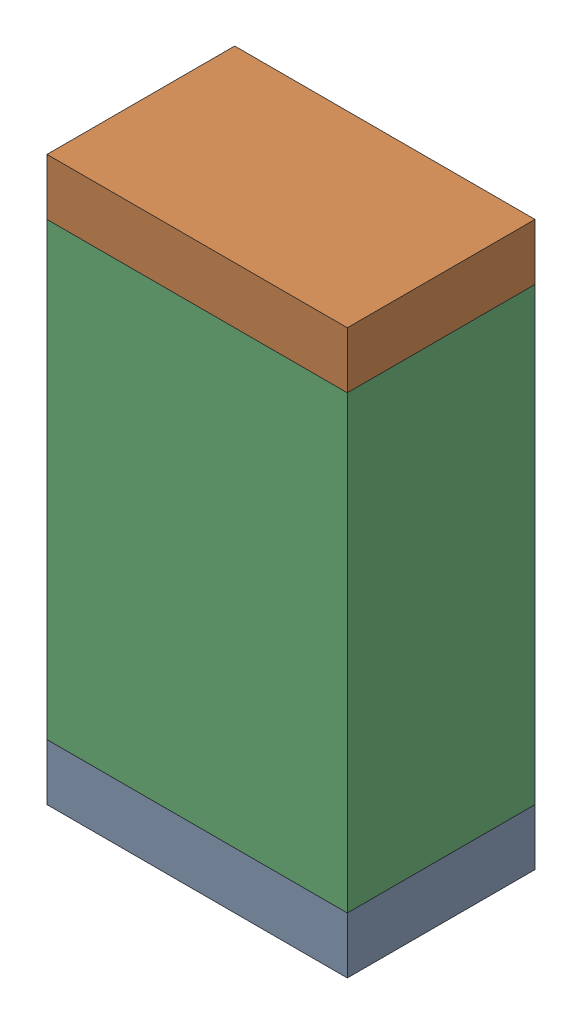
SolidWorks assembly C85, configuration Default. Lengths in mm.
Overall size (0.8 1.5 0.5).
6 component instances, 2 part files, 0 mates.
Components (placement in the parent):
- 810156592-1: 810156592 [Default] at (128.3 63.675 0) size (0.8 0.15 0.5)
  - Extruded_7-1: Extruded_7 [Default] at origin size (0.8 0.15 0.5)
- 810156592-2: 810156592 [Default] at (128.3 65.025 0) size (0.8 0.15 0.5)
  - Extruded_7-1: Extruded_7 [Default] at origin size (0.8 0.15 0.5)
- 810156976-1: 810156976 [Default] at (128.3 64.35 0) size (0.8 1.2 0.5)
  - Extruded_6-1: Extruded_6 [Default] at origin size (0.8 1.2 0.5)
